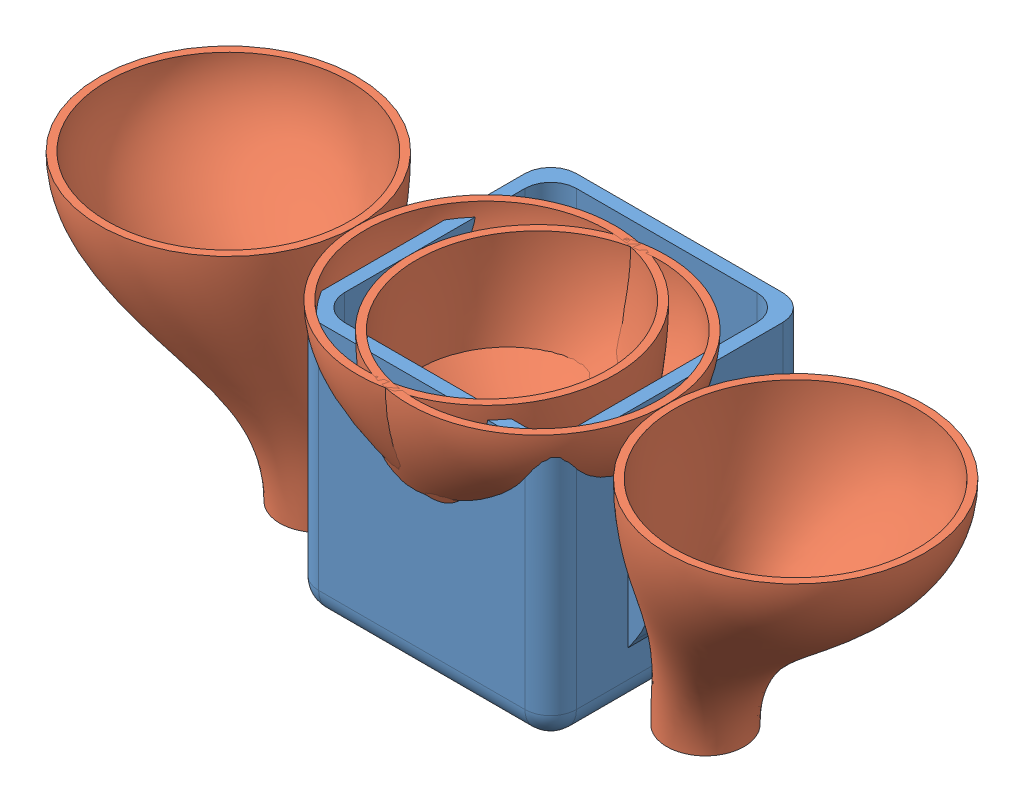
SolidWorks assembly sc_assembly, configuration Default. Lengths in mm.
Overall size (331.55 105.12 120.78).
3 component instances, 2 part files, 4 mates.
Components (placement in the parent):
- sc_body-2: sc_body [Default] at (-39.5982 -41.7707 -70) size (120 100 100)
- sc_container-2: sc_container [Default] at (120.4018 63.2293 -105) x (1 0 0) z (0 0 -1) size (231.55 100.25 110.3)
- sc_container-3: sc_container [Default] at (-99.5982 63.2293 -105) x (-1 0 0) z (0 0 1) size (231.55 100.25 110.3)
Mates (geometry in assembly coordinates):
- Coincident5: coincident anti-aligned: circle of sc_container-2; circle of sc_body-2
- Coincident6: coincident aligned: plane of sc_body-2 through (70.4018 8.2293 -100) normal (0 0 1); plane of sc_container-2 through (500120.4018 48.2293 -100) normal (0 0 1)
- Coincident7: coincident anti-aligned: circle of sc_body-2; circle of sc_container-3
- Coincident8: coincident aligned: plane of sc_body-2 through (-49.5982 8.2293 -100) normal (0 0 1); plane of sc_container-3 through (-500099.5982 48.2293 -100) normal (0 0 1)
